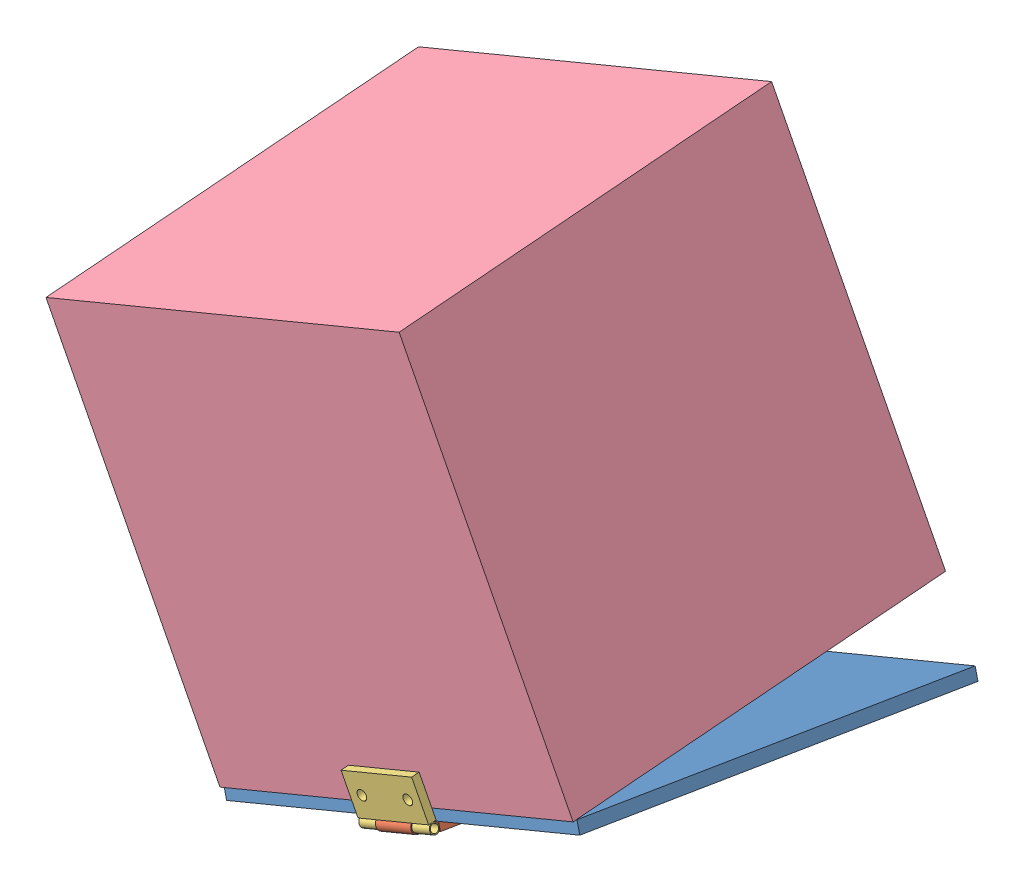
SolidWorks assembly pump box, configuration Default. Lengths in mm.
Overall size (280.23 306.88 212.9).
4 component instances, 4 part files, 8 mates.
Components (placement in the parent):
- box lid-1: box lid [Default] at (124.3407 142.2191 -5.2612) x (-0.050527 0.121847 0.991262) z (-0.379702 0.915656 -0.131908) size (200 200 6)
- hinge1-1: hinge1 [Default] at (120.5527 151.3541 84.2162) x (-0.923728 -0.383049 0) z (0.379702 -0.915656 0.131908) size (40 25.5 6)
- hinge2-1: hinge2 [Default] at (115.1422 164.4016 97.3814) x (0.923728 0.383049 0) z (0.023628 -0.05698 0.998096) size (40 25 5)
- pump-1: pump [Default] at (114.6437 165.6037 -4.7328) x (0.923728 0.383049 0) z (-0.38232 0.921969 0.061685) size (200 200 205)
Mates (geometry in assembly coordinates):
- Coincident1: coincident: plane of box lid-1 through (124.3407 142.2191 -5.2612) normal (0.379702 -0.915656 0.131908); plane of hinge1-1 through (119.7933 153.1854 83.9524) normal (-0.379702 0.915656 -0.131908)
- Coincident2: coincident: circle of box lid-1; circle of hinge1-1
- Coincident3: coincident: circle of box lid-1; circle of hinge1-1
- Coincident4: coincident: plane of hinge2-1 through (115.0949 164.5155 95.3852) normal (-0.023628 0.05698 -0.998096); plane of pump-1 through (-51.8302 305.9946 107.4138) normal (0.023628 -0.05698 0.998096)
- Coincident8: coincident: circle of hinge2-1; circle of pump-1
- Coincident9: coincident: circle of hinge2-1; circle of pump-1
- Concentric4: concentric: cylinder of hinge1-1 through (110.6838 149.0467 96.607) axis (0.923728 0.383049 0) radius 2; cylinder of hinge2-1 through (138.3956 160.5381 96.607) axis (-0.923728 -0.383049 0) radius 2
- Coincident10: coincident: plane of hinge1-1 through (129.1584 156.7077 96.607) normal (0.923728 0.383049 0); plane of hinge2-1 through (128.1318 159.1833 93.7702) normal (-0.923728 -0.383049 0)
